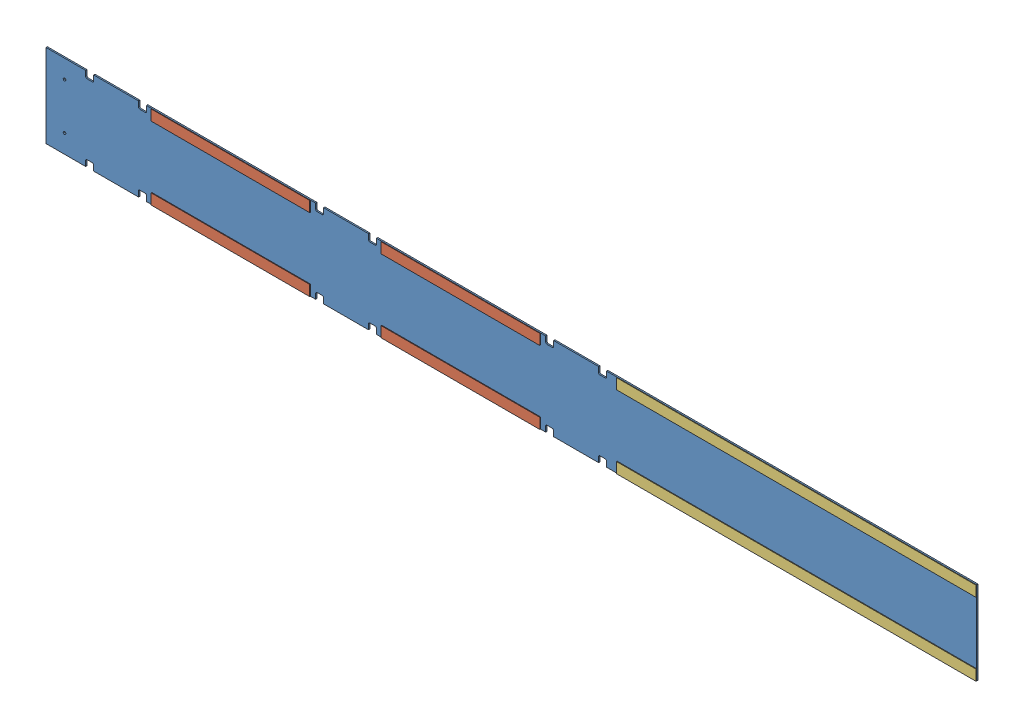
SolidWorks assembly GE-19228, configuration Default. Lengths in mm.
Overall size (2235.2 200.03 4.76).
7 component instances, 3 part files, 21 mates.
Components (placement in the parent):
- GE-19228-1: GE-19228 [Default] at origin size (2235.2 200.03 3.17)
- Loop_1_15-1: Loop_1_15 [Default] at (-863.6 -74.6125 4.7625) x (1 0 0) z (0 1 0) size (381 1.59 25.4)
- Loop_1_34-1: Loop_1_34 [Default] at (254 -74.6125 4.7625) x (1 0 0) z (0 1 0) size (863.6 1.59 25.4)
- Loop_1_15-2: Loop_1_15 [Default] at (-311.15 -74.6125 4.7625) x (1 0 0) z (0 1 0) size (381 1.59 25.4)
- Loop_1_15-3: Loop_1_15 [Default] at (-863.6 100.0125 4.7625) x (1 0 0) z (0 1 0) size (381 1.59 25.4)
- Loop_1_15-4: Loop_1_15 [Default] at (-311.15 100.0125 4.7625) x (1 0 0) z (0 1 0) size (381 1.59 25.4)
- Loop_1_34-2: Loop_1_34 [Default] at (254 100.0125 4.7625) x (1 0 0) z (0 1 0) size (863.6 1.59 25.4)
Mates (geometry in assembly coordinates):
- Coincident1: coincident: plane of GE-19228-1 through (0 0 3.175) normal (0 0 1); plane of Loop_1_34-1 through (254 -74.6125 3.175) normal (0 0 -1)
- Coincident5: coincident: plane of GE-19228-1 through (-1117.6 -100.0125 3.175) normal (0 -1 0); plane of Loop_1_34-1 through (254 -100.0125 3.175) normal (0 -1 0)
- Coincident6: coincident: plane of GE-19228-1 through (1117.6 -100.0125 3.175) normal (1 0 0); plane of Loop_1_34-1 through (1117.6 -74.6125 3.175) normal (1 0 0)
- Coincident7: coincident: plane of GE-19228-1 through (0 0 3.175) normal (0 0 1); plane of Loop_1_15-1 through (-863.6 -74.6125 3.175) normal (0 0 -1)
- Coincident8: coincident: line of GE-19228-1; line of Loop_1_15-1 through (-482.6 -100.0125 4.7625) axis (-1 0 0)
- Coincident9: coincident: plane of GE-19228-1 through (0 0 3.175) normal (0 0 1); plane of Loop_1_15-2 through (-311.15 -74.6125 3.175) normal (0 0 -1)
- Coincident10: coincident: plane of GE-19228-1 through (-1117.6 -100.0125 3.175) normal (0 -1 0); line of Loop_1_15-2 through (69.85 -100.0125 4.7625) axis (-1 0 0)
- Distance1: distance = 254 mm: plane of Loop_1_15-1 through (-863.6 -74.6125 3.175) normal (-1 0 0); plane of GE-19228-1 through (-1117.6 -100.0125 3.175) normal (-1 0 0)
- Distance2: distance = 171.45 mm: plane of assembly; plane of assembly; plane of Loop_1_15-1 through (-482.6 -74.6125 3.175) normal (1 0 0); plane of Loop_1_15-2 through (-311.15 -74.6125 3.175) normal (-1 0 0)
- Coincident11: coincident: plane of GE-19228-1 through (0 0 0) normal (0 0 -1); plane of ? through (-863.6 -74.6125 0) normal (0 0 1)
- Coincident13: coincident: plane of GE-19228-1 through (0 0 0) normal (0 0 -1); plane of ? through (-311.15 -74.6125 0) normal (0 0 1)
- Coincident14: coincident: plane of GE-19228-1 through (0 0 0) normal (0 0 -1); plane of ? through (254 -74.6125 0) normal (0 0 1)
- Coincident15: coincident: plane of GE-19228-1 through (0 0 3.175) normal (0 0 1); plane of Loop_1_15-3 through (-863.6 100.0125 3.175) normal (0 0 -1)
- Coincident16: coincident: plane of GE-19228-1 through (0 0 3.175) normal (0 0 1); plane of Loop_1_15-4 through (-311.15 100.0125 3.175) normal (0 0 -1)
- Coincident17: coincident: plane of GE-19228-1 through (0 0 3.175) normal (0 0 1); plane of Loop_1_34-2 through (254 100.0125 3.175) normal (0 0 -1)
- Coincident18: coincident: plane of GE-19228-1 through (-1117.6 100.0125 3.175) normal (0 1 0); plane of Loop_1_34-2 through (254 100.0125 3.175) normal (0 1 0)
- Coincident19: coincident: plane of assembly; plane of assembly; plane of Loop_1_34-1 through (1117.6 -74.6125 3.175) normal (1 0 0); plane of Loop_1_34-2 through (1117.6 100.0125 3.175) normal (1 0 0)
- Coincident20: coincident: plane of GE-19228-1 through (-1117.6 100.0125 3.175) normal (0 1 0); plane of Loop_1_15-4 through (-311.15 100.0125 3.175) normal (0 1 0)
- Coincident21: coincident: plane of assembly; plane of assembly; plane of Loop_1_15-2 through (69.85 -74.6125 3.175) normal (1 0 0); plane of Loop_1_15-4 through (69.85 100.0125 3.175) normal (1 0 0)
- Coincident22: coincident: plane of GE-19228-1 through (-1117.6 100.0125 3.175) normal (0 1 0); plane of Loop_1_15-3 through (-863.6 100.0125 3.175) normal (0 1 0)
- Coincident23: coincident: plane of assembly; plane of assembly; plane of Loop_1_15-1 through (-482.6 -74.6125 3.175) normal (1 0 0); plane of Loop_1_15-3 through (-482.6 100.0125 3.175) normal (1 0 0)
